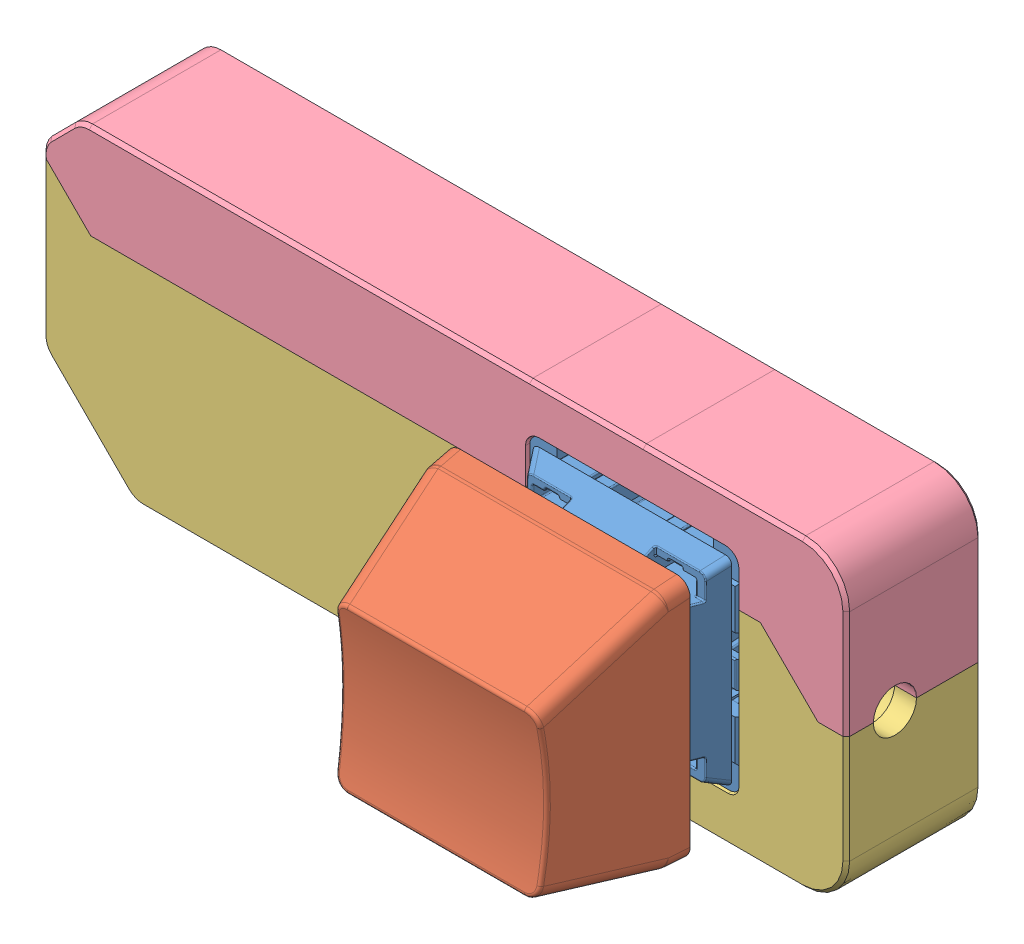
SolidWorks assembly latency-tester-assy, configuration Default. Lengths in mm.
Overall size (59.5 22.5 26.24).
4 component instances, 4 part files, 9 mates.
Components (placement in the parent):
- reflex_pcb-1: reflex_pcb [Default] at (121.6215 124.8192 29.8255) x (0 -1 0) z (0 0 1) size (20.93 55.43 19.61)
- mx-keycap-1: mx-keycap [Default] at (43.1775 33.8291 42.5755) x (-0.000004 -1 0) z (-1 0.000004 0) size (18 11.34 18)
- shell-1: shell [Default] at (-8.2642 14.8329 31.8255) size (59.5 19.05 10)
- shell-top-1: shell-top [Default] at (-8.2642 14.8329 31.8255) size (59.5 11.25 10)
Mates (geometry in assembly coordinates):
- Width1: width anti-aligned: plane of mx-keycap-1 through (34.8025 22.6792 54.017) normal (0.000004 1 0); plane of mx-keycap-1 through (33.5525 26.9792 54.017) normal (0.000004 -1 0); plane of reflex_pcb-1 through (33.5515 22.8292 47.2755) normal (0 -1 0); plane of reflex_pcb-1 through (33.5515 26.8292 47.2755) normal (0 1 0)
- Coincident7: coincident anti-aligned: plane of reflex_pcb-1 through (34.2015 24.8292 43.5755) normal (0 0 1); plane of mx-keycap-1 through (43.1775 33.8291 43.5755) normal (0 0 -1)
- Lock1: lock: unknown of reflex_pcb-1; unknown of mx-keycap-1
- Coincident8: coincident aligned: plane of shell-1 through (-8.2642 37.0177 27.8255) normal (0 0 -1); plane of shell-top-1 through (-8.2642 37.0177 27.8255) normal (0 0 -1)
- Coincident9: coincident aligned: plane of shell-1 through (49.9865 37.0177 27.8255) normal (1 0 0); plane of shell-top-1 through (49.9865 37.0177 27.8255) normal (1 0 0)
- Coincident11: coincident anti-aligned: plane of shell-1 through (-8.2642 51.2639 27.8255) normal (0 1 0); plane of shell-top-1 through (-8.2642 51.2639 27.8255) normal (0 -1 0)
- Width2: width aligned: plane of shell-1 through (3.4115 43.7639 31.0755) normal (1 0 0); plane of shell-1 through (14.2115 43.7639 31.0755) normal (-1 0 0); plane of reflex_pcb-1 through (13.546 23.1169 34.9396) normal (1 0 0); plane of reflex_pcb-1 through (4.077 23.1169 34.9396) normal (-1 0 0)
- Width3: width anti-aligned: plane of shell-1 through (41.5492 -499962.9823 31.9255) normal (0 0 -1); plane of shell-1 through (-8.2642 37.0177 29.7255) normal (0 0 1); plane of reflex_pcb-1 through (46.6215 16.8192 31.8255) normal (0 0 1); plane of reflex_pcb-1 through (46.6215 16.8192 29.8255) normal (0 0 -1)
- Width4: width anti-aligned: plane of shell-1 through (26.2365 16.9292 32.0755) normal (0 1 0); plane of shell-top-1 through (26.2365 32.7292 32.0755) normal (0 -1 0); plane of reflex_pcb-1 through (42.0015 17.0292 36.8755) normal (0 -1 0); plane of reflex_pcb-1 through (42.0015 32.6292 36.8755) normal (0 1 0)
